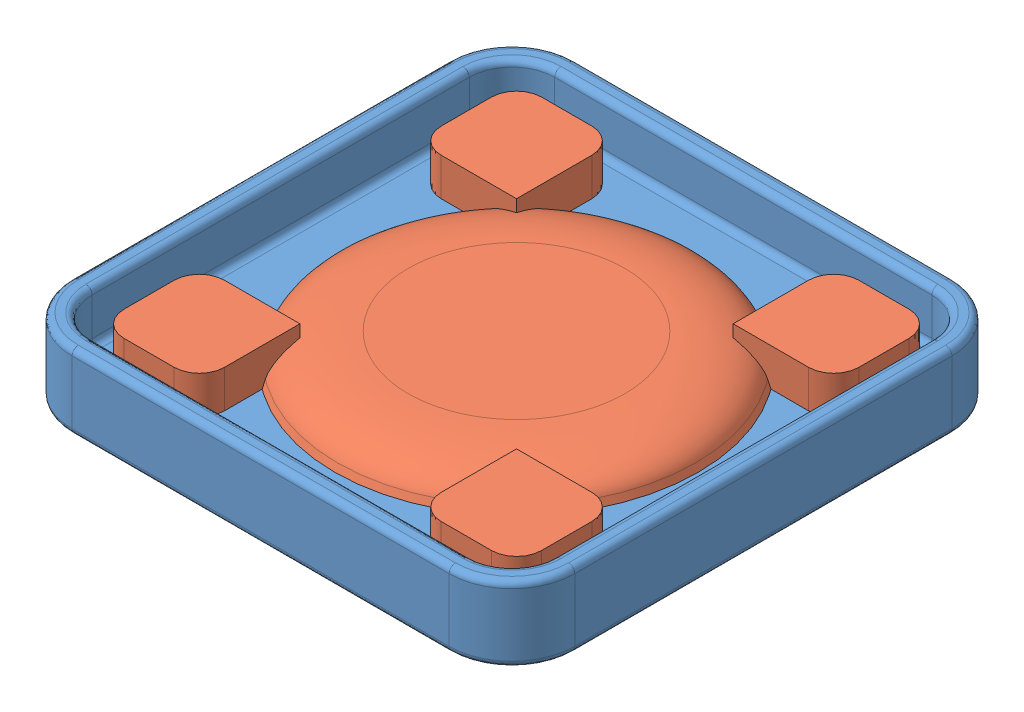
SolidWorks assembly GlyniumPlanet, configuration Default. Lengths in mm.
Overall size (40 6 40).
2 component instances, 2 part files, 2 mates.
Components (placement in the parent):
- Tile-1: Tile [Default] at (14.4723 18.5164 32.5472) size (40 6 40)
- GlumiumPlanet4-1: GlumiumPlanet4 [Default] at (14.4324 20.5164 32.1472) size (33.23 3 33.23)
Mates (geometry in assembly coordinates):
- Coincident1: coincident anti-aligned: plane of Tile-1 through (-0.5277 20.5164 47.5472) normal (0 1 0); plane of GlumiumPlanet4-1 through (14.4324 20.5164 32.1472) normal (0 -1 0)
- Coincident2: coincident anti-aligned: line of Tile-1 through (29.4723 20.5164 14.6472) axis (-1 0 0); line of GlumiumPlanet4-1 through (-3.0676 20.5164 14.6472) axis (1 0 0)
